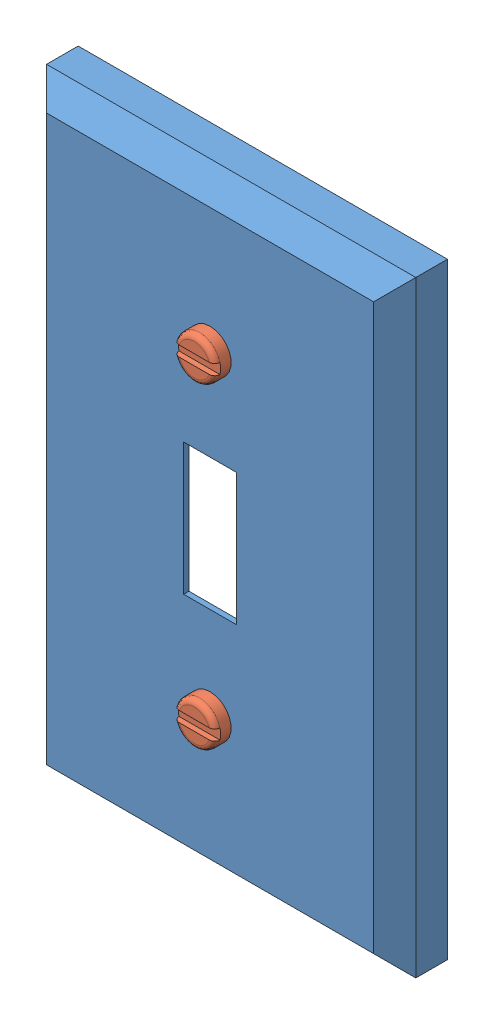
SolidWorks assembly Sestava3, configuration Výchozí. Lengths in mm.
Overall size (70 115 18.07).
3 component instances, 2 part files, 6 mates.
Components (placement in the parent):
- vypinac-1: vypinac [Výchozí] at (-171.014 -120.1459 29.6705) size (70 115 10)
- sroub-1: sroub [Výchozí] at (-136.014 -32.6459 24.6705) x (0 1 0) z (0 0 1) size (8 8 18.07)
- sroub-2: sroub [Výchozí] at (-136.014 -92.6459 24.6705) x (0 -1 0) z (0 0 1) size (8 8 18.07)
Mates (geometry in assembly coordinates):
- Soustředná1: concentric: circle of vypinac-1 centre (-136.014 -92.6459 39.6705) axis (0 0 1); circle of sroub-2 centre (-136.014 -92.6459 26.4205) axis (0 0 1)
- Soustředná2: concentric aligned: circle of vypinac-1 centre (-136.014 -32.6459 39.6705) axis (0 0 1); circle of sroub-1 centre (-136.014 -32.6459 26.4205) axis (0 0 1)
- Sjednocená2: coincident: plane of vypinac-1 through (-171.014 -5.1459 39.6705) normal (0 0 1); plane of sroub-2 through (-136.014 -92.6459 39.6705) normal (0 0 -1)
- Sjednocená3: coincident anti-aligned: plane of vypinac-1 through (-171.014 -5.1459 39.6705) normal (0 0 1); plane of sroub-1 through (-136.014 -32.6459 39.6705) normal (0 0 -1)
- Rovnoběžná1: parallel aligned: line of vypinac-1; line of sroub-1
- Rovnoběžná2: parallel aligned: line of vypinac-1; line of sroub-2
